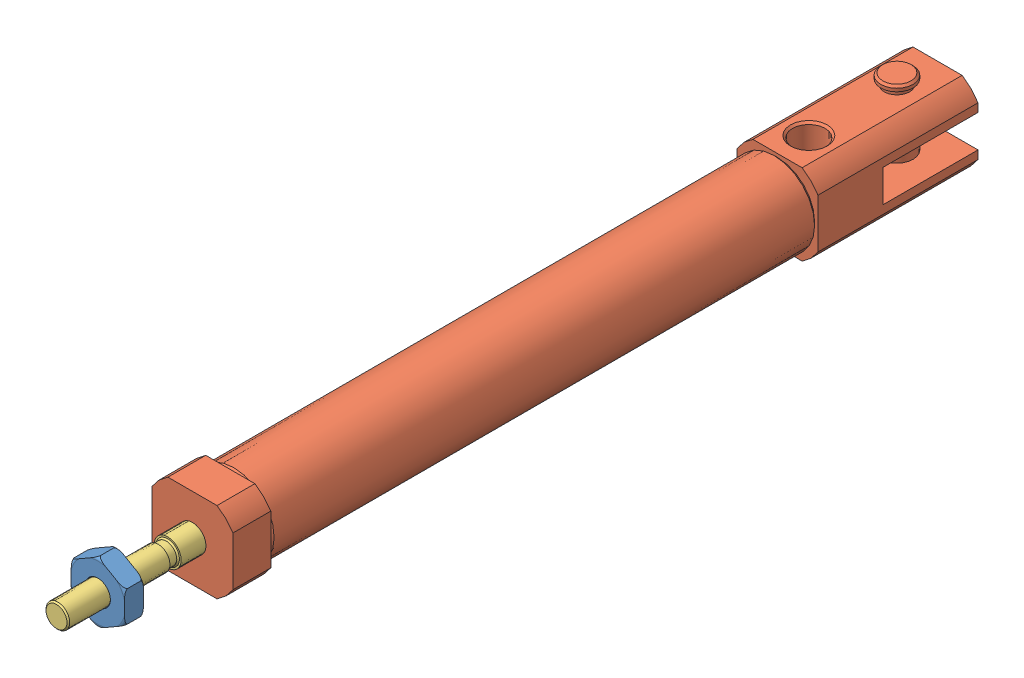
SolidWorks assembly NCJ2D10-200S, configuration Default. Lengths in mm.
Overall size (11.94 14.99 130.05).
3 component instances, 3 part files, 0 mates.
Components (placement in the parent):
- NCJ2D10-200S.step_NCJ2-Nut_10R-1: NCJ2D10-200S.step_NCJ2-Nut_10R [Default] at (0 0 58.54) size (8.86 9.6 3.3)
- NCJ2D10-200S.step_NCJ2-Body_10DS-1: NCJ2D10-200S.step_NCJ2-Body_10DS [Default] at origin size (11.94 14.99 109.98)
- NCJ2D10-200S.step_NCJ2-Rod_10-1: NCJ2D10-200S.step_NCJ2-Rod_10 [Default] at (0 0 -25.4) size (10 10 93.94)
